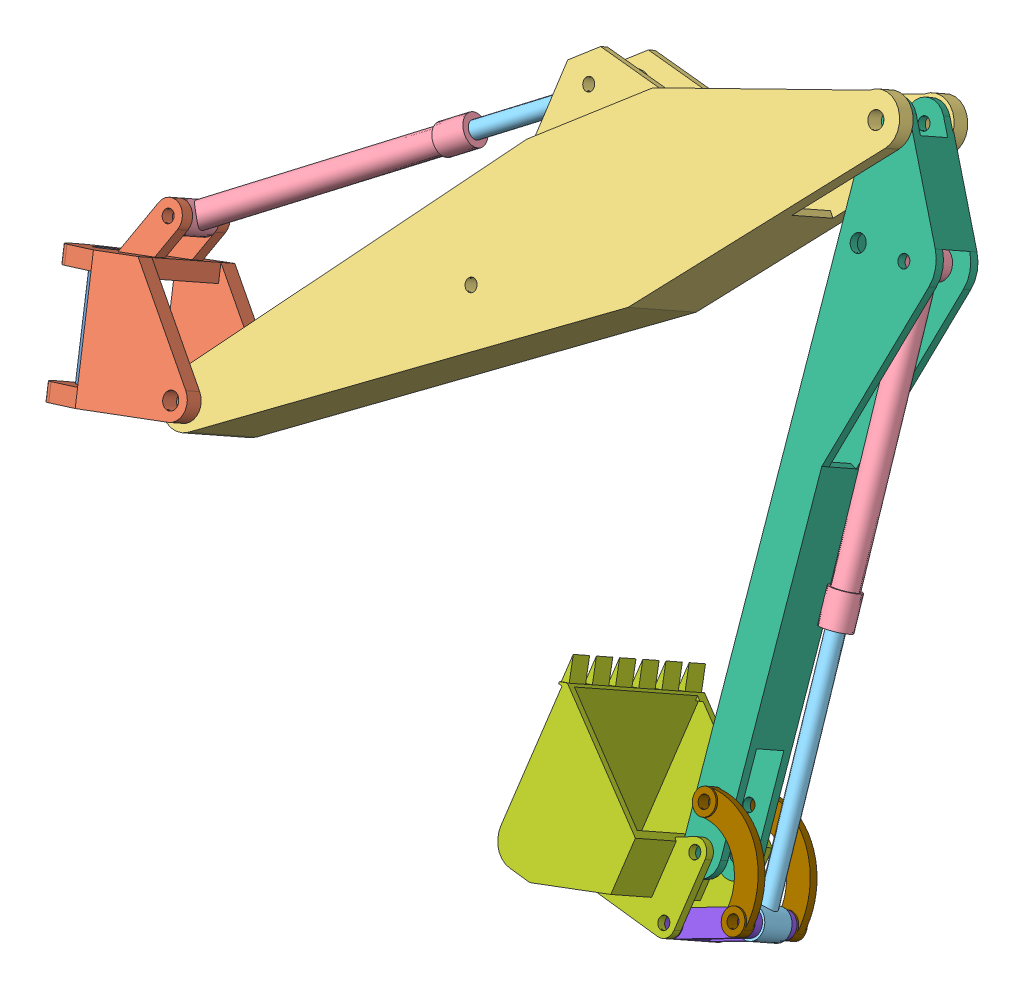
SolidWorks assembly BACK HOE ASSEMBLY, configuration Default. Lengths in mm.
Overall size (5757.61 4649.91 3023.73).
12 component instances, 9 part files, 27 mates.
Components (placement in the parent):
- Part6-1: Part6 [Default] at (653.2181 32.6016 676.2537) x (-0.3025 0.832392 -0.464345) z (-0.15538 -0.523718 -0.837602) size (765 150 150)
- part 2-1: part 2 [Default] at (862.1809 145.2172 742.0002) x (-0.952125 -0.286467 0.106742) z (0.044168 -0.474404 -0.879198) size (1129.2 1060 710)
- Part8-1: Part8 [Default] at (4793.7848 3059.2999 -745.4934) x (-0.749719 -0.597392 0.284682) z (0.044168 -0.474404 -0.879198) size (4825 1275 500)
- Part4-1: Part4 [Default] at (2298.3275 1991.9296 -298.3299) x (-0.794205 -0.550547 0.25717) z (0.044168 -0.474404 -0.879198) size (1915 180 200)
- Part5-1: Part5 [Default] at (3019.5204 2491.864 -531.8578) x (-0.794205 -0.550547 0.25717) z (0.044168 -0.474404 -0.879198) size (1890 180 200)
- Part1-1: Part1 [Default] at (5256.7462 -54.0164 1128.2804) x (-0.128302 0.870076 -0.475927) z (0.044168 -0.474404 -0.879198) size (3914 637 306)
- Part3-1: Part3 [Default] at (4319.1557 -534.3744 1166.3518) x (-0.044168 0.474404 0.879198) z (0.074042 0.879191 -0.470681) size (1006 1010 1068)
- Part7-1: Part7 [Default] at (5652.5666 -287.2791 1100.0087) x (0.044168 -0.474404 -0.879198) z (0.907758 0.386543 -0.162971) size (306 150 610)
- Part9-1: Part9 [Default] at (5433.4972 -7.1339 1155.0839) x (-0.690601 0.621423 -0.370005) z (0.044168 -0.474404 -0.879198) size (760 303.34 76)
- Part9-2: Part9 [Default] at (5450.3694 -188.3564 819.2301) x (-0.690601 0.621423 -0.370005) z (0.044168 -0.474404 -0.879198) size (760 303.34 76)
- Part4-2: Part4 [Default] at (5439.5647 984.4925 403.0762) x (-0.145317 0.867646 -0.475471) z (0.044168 -0.474404 -0.879198) size (1915 180 200)
- Part5-2: Part5 [Default] at (5652.5666 -287.2791 1100.0087) x (-0.145317 0.867646 -0.475471) z (-0.044168 0.474404 0.879198) size (1890 180 200)
Mates (geometry in assembly coordinates):
- Concentric1: concentric anti-aligned: cylinder of Part6-1 through (653.2181 32.6016 676.2537) axis (0.3025 -0.832392 0.464345) radius 75; cylinder of part 2-1 through (452.6605 584.4779 368.3929) axis (-0.3025 0.832392 -0.464345) radius 75
- Coincident2: coincident aligned: plane of Part6-1 through (421.8055 669.3819 321.0297) normal (-0.3025 0.832392 -0.464345); plane of part 2-1 through (922.3089 646.8377 -45.439) normal (-0.3025 0.832392 -0.464345)
- Concentric2: concentric aligned: cylinder of part 2-1 through (1385.7585 523.0905 852.1695) axis (0.044168 -0.474404 -0.879198) radius 51; cylinder of Part8-1 through (1390.2636 474.7012 762.4913) axis (0.044168 -0.474404 -0.879198) radius 51
- Coincident11: coincident anti-aligned: plane of part 2-1 through (1390.2636 474.7012 762.4913) normal (0.044168 -0.474404 -0.879198); plane of Part8-1 through (4782.7428 3177.901 -525.6939) normal (-0.044168 0.474404 0.879198)
- Concentric3: concentric anti-aligned: cylinder of Part8-1 through (3008.3458 2611.8883 -309.4206) axis (0.044168 -0.474404 -0.879198) radius 38; cylinder of Part5-1 through (3023.9372 2444.4236 -619.7776) axis (-0.044168 0.474404 0.879198) radius 38
- Coincident12: coincident anti-aligned: plane of Part8-1 through (3015.1036 2539.3045 -443.938) normal (0.044168 -0.474404 -0.879198); plane of Part5-1 through (3015.1036 2539.3045 -443.938) normal (-0.044168 0.474404 0.879198)
- Concentric6: concentric anti-aligned: cylinder of part 2-1 through (841.1738 1070.2022 324.8648) axis (0.044168 -0.474404 -0.879198) radius 38; cylinder of Part4-1 through (853.32 939.741 83.0852) axis (-0.044168 0.474404 0.879198) radius 38
- Coincident13: coincident anti-aligned: plane of part 2-1 through (853.32 939.741 83.0852) normal (-0.044168 0.474404 0.879198); plane of Part4-1 through (853.32 939.741 83.0852) normal (0.044168 -0.474404 -0.879198)
- Concentric8: concentric aligned: cylinder of Part4-1 through (2298.3275 1991.9296 -298.3299) axis (0.794205 0.550547 -0.25717) radius 51; cylinder of Part5-1 through (3019.5204 2491.864 -531.8578) axis (0.794205 0.550547 -0.25717) radius 51
- LimitDistance2: limit distance = 887.6897 mm: plane of Part5-1 through (1589.9512 1500.8796 -68.9521) normal (-0.794205 -0.550547 0.25717); line of part 2-1 through (939.7759 875.7562 36.6489) axis (-0.044168 0.474404 0.879198)
- Concentric10: concentric anti-aligned: cylinder of Part8-1 through (4782.7428 3177.901 -525.6939) axis (0.044168 -0.474404 -0.879198) radius 51; cylinder of Part1-1 through (4800.6751 2985.2928 -882.6484) axis (-0.044168 0.474404 0.879198) radius 38
- Coincident14: coincident anti-aligned: plane of Part8-1 through (4787.1596 3130.4606 -613.6137) normal (0.044168 -0.474404 -0.879198); plane of Part1-1 through (5167.6031 2640.5307 -330.1415) normal (-0.044168 0.474404 0.879198)
- Concentric11: concentric anti-aligned: cylinder of Part1-1 through (5270.2616 -199.1841 859.2458) axis (-0.044168 0.474404 0.879198) radius 38; cylinder of Part3-1 through (5254.5378 -30.2962 1172.2404) axis (0.044168 -0.474404 -0.879198) radius 38
- Coincident15: coincident anti-aligned: plane of Part1-1 through (5167.6031 2640.5307 -330.1415) normal (-0.044168 0.474404 0.879198); plane of Part3-1 through (5228.2401 -392.505 1309.4926) normal (0.044168 -0.474404 -0.879198)
- Concentric13: concentric anti-aligned: cylinder of Part3-1 through (5226.0317 -368.7848 1353.4525) axis (0.044168 -0.474404 -0.879198) radius 38; cylinder of Part7-1 through (5241.7556 -537.6727 1040.4579) axis (-0.044168 0.474404 0.879198) radius 38
- Coincident19: coincident aligned: circle of Part3-1; plane of Part7-1 through (5645.8089 -214.6952 1234.526) normal (-0.044168 0.474404 0.879198)
- Coincident20: coincident anti-aligned: plane of Part7-1 through (5645.8089 -214.6952 1234.526) normal (-0.044168 0.474404 0.879198); plane of Part9-1 through (5435.1756 -25.1613 1121.6743) normal (0.044168 -0.474404 -0.879198)
- Concentric14: concentric anti-aligned: cylinder of Part7-1 through (5645.8089 -214.6952 1234.526) axis (0.044168 -0.474404 -0.879198) radius 38; cylinder of Part9-1 through (5645.8089 -214.6952 1234.526) axis (-0.044168 0.474404 0.879198) radius 38
- Concentric16: concentric aligned: cylinder of Part1-1 through (5238.0577 19.2049 739.788) axis (-0.044168 0.474404 0.879198) radius 38; cylinder of Part9-1 through (5224.5423 164.3726 1008.8227) axis (-0.044168 0.474404 0.879198) radius 38
- Concentric17: concentric aligned: cylinder of Part7-1 through (5659.3244 -359.8629 965.4913) axis (-0.044168 0.474404 0.879198) radius 38; cylinder of Part9-2 through (5662.6812 -395.9177 898.6722) axis (-0.044168 0.474404 0.879198) radius 38
- Coincident23: coincident anti-aligned: plane of Part7-1 through (5659.3244 -359.8629 965.4913) normal (0.044168 -0.474404 -0.879198); plane of Part9-2 through (5448.6911 -170.329 852.6396) normal (-0.044168 0.474404 0.879198)
- Concentric18: concentric aligned: cylinder of Part1-1 through (5238.0577 19.2049 739.788) axis (-0.044168 0.474404 0.879198) radius 38; cylinder of Part9-2 through (5241.4145 -16.8498 672.9689) axis (-0.044168 0.474404 0.879198) radius 38
- Concentric19: concentric aligned: cylinder of Part1-1 through (5181.1186 2495.363 -599.1761) axis (-0.044168 0.474404 0.879198) radius 38; cylinder of Part4-2 through (5178.7776 2520.5064 -552.5786) axis (-0.044168 0.474404 0.879198) radius 38
- Coincident25: coincident aligned: circle of Part1-1; plane of Part4-2 through (5178.7776 2520.5064 -552.5786) normal (0.044168 -0.474404 -0.879198)
- Concentric20: concentric anti-aligned: cylinder of Part7-1 through (5659.3244 -359.8629 965.4913) axis (-0.044168 0.474404 0.879198) radius 38; cylinder of Part5-2 through (5648.1498 -239.8387 1187.9285) axis (0.044168 -0.474404 -0.879198) radius 38
- Coincident26: coincident anti-aligned: plane of Part7-1 through (5656.9835 -334.7195 1012.0888) normal (-0.044168 0.474404 0.879198); plane of Part5-2 through (5656.9835 -334.7195 1012.0888) normal (0.044168 -0.474404 -0.879198)
- Coincident27: coincident aligned: circle of Part4-2; cylinder of Part5-2 through (5652.5666 -287.2791 1100.0087) axis (0.145317 -0.867646 0.475471) radius 51
